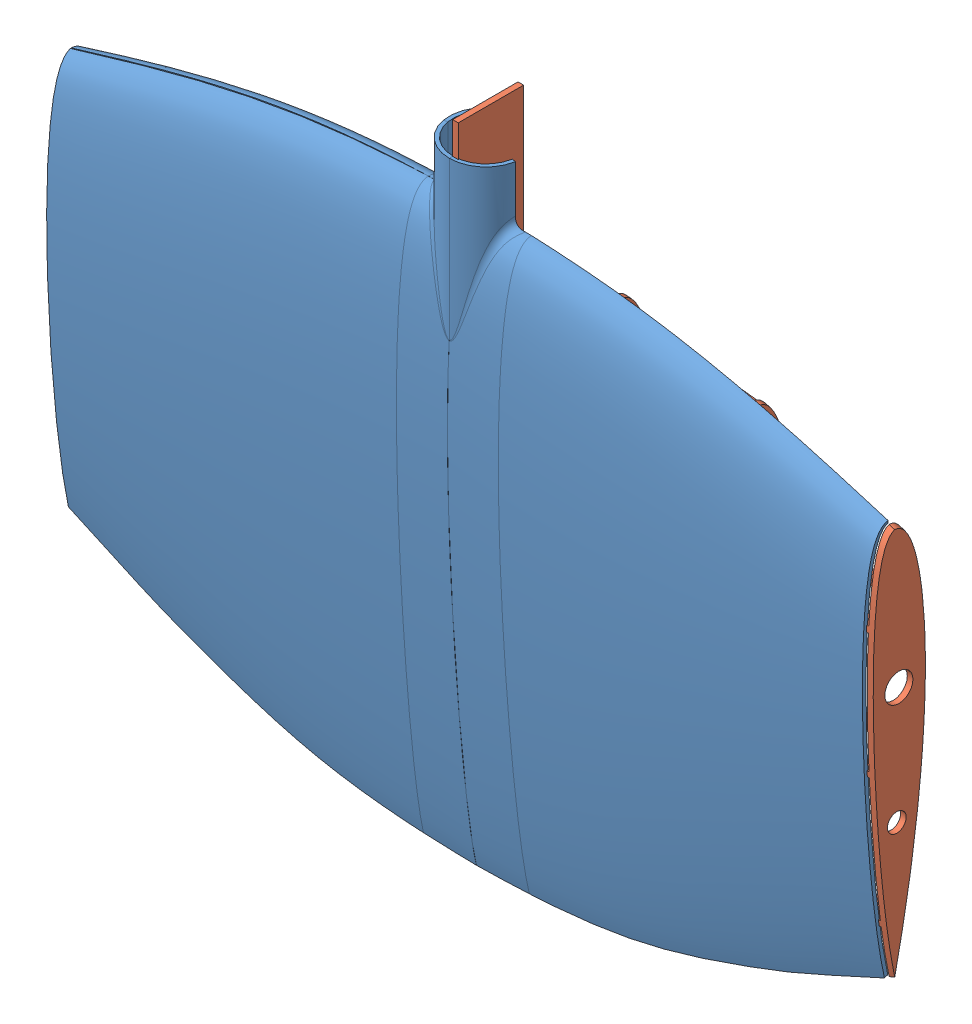
SolidWorks assembly Assem2, configuration Default. Lengths in mm.
Overall size (443.23 358.41 54.23).
2 component instances, 2 part files, 1 mates.
Components (placement in the parent):
- Body2-1: Body2 [Default] at (-272.8436 -181.0097 840.7168) size (438.51 341.43 54.23)
- Frame_structure-1: Frame_structure [Default] at (-271.3436 -181.027 840.9864) size (442.57 350.41 45.37)
Mates (geometry in assembly coordinates):
- Coincident1: coincident anti-aligned: plane of Body2-1 through (402.1564 -181.0097 840.7168) normal (1 0 0); plane of Frame_structure-1 through (402.1564 697.2594 819.3463) normal (-1 0 0)
